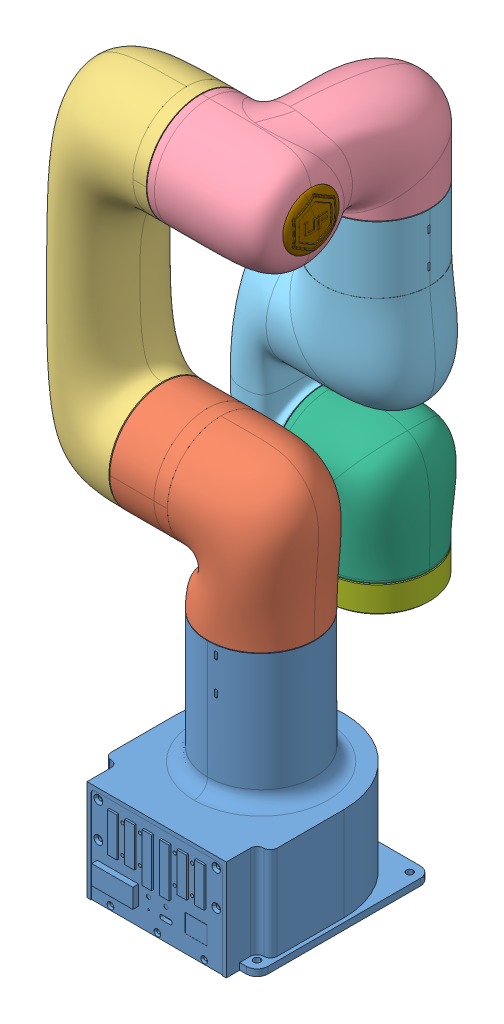
SolidWorks assembly Lite 6, configuration ﾃﾞﾌｫﾙﾄ. Lengths in mm.
Overall size (202.79 483.73 214.58).
10 component instances, 9 part files, 0 mates.
Components (placement in the parent):
- Lite 6.STEP-1: Lite 6.STEP [ﾃﾞﾌｫﾙﾄ] at origin size (202.79 483.73 214.58)
  - JOINT I.STEP-1: JOINT I.STEP [ﾃﾞﾌｫﾙﾄ] at origin size (130 173 143.58)
  - JOINT II.STEP-1: JOINT II.STEP [ﾃﾞﾌｫﾙﾄ] at (-54.5611 164.6479 -6.4973) x (1 0 0) z (0 1 0) size (115.93 80.26 110.12)
  - JOINT III.STEP-1: JOINT III.STEP [ﾃﾞﾌｫﾙﾄ] at origin size (92.09 280 80.52)
  - JOINT IV.STEP-1: JOINT IV.STEP [ﾃﾞﾌｫﾙﾄ] at (78.7495 341.4089 73.2537) x (-1 0 0) z (0 1 0) size (84.26 166.58 80.05)
  - JOINT V.STEP-1: JOINT V.STEP [ﾃﾞﾌｫﾙﾄ] at (-6.7383 129.2636 -127.9218) x (-1 0 0) z (0 1 0) size (152.28 84.32 229.86)
  - JOINT VI.STEP-1: JOINT VI.STEP [ﾃﾞﾌｫﾙﾄ] at (79.2495 310.7989 73.2537) x (-1 0 0) z (0 1 0) size (85.89 77.86 93.78)
  - ________.STEP-1: ________.STEP [ﾃﾞﾌｫﾙﾄ] at (18.7336 88.6056 -95.1394) x (-1 0 0) z (0 0 -1) size (77.5 24.5 77.5)
  - M8________.STEP-1: M8________.STEP [ﾃﾞﾌｫﾙﾄ] at (18.7336 97.6056 -141.1394) x (-1 0 0) z (0 0 1) size (12.7 11 19.8)
  - Logo Rubber Cap(1).STEP-1: Logo Rubber Cap(1).STEP [ﾃﾞﾌｫﾙﾄ] at (45.5234 378.7156 -8.1394) x (0 0.271368 -0.962476) z (0 -0.962476 -0.271368) size (50.65 15.37 49.19)
